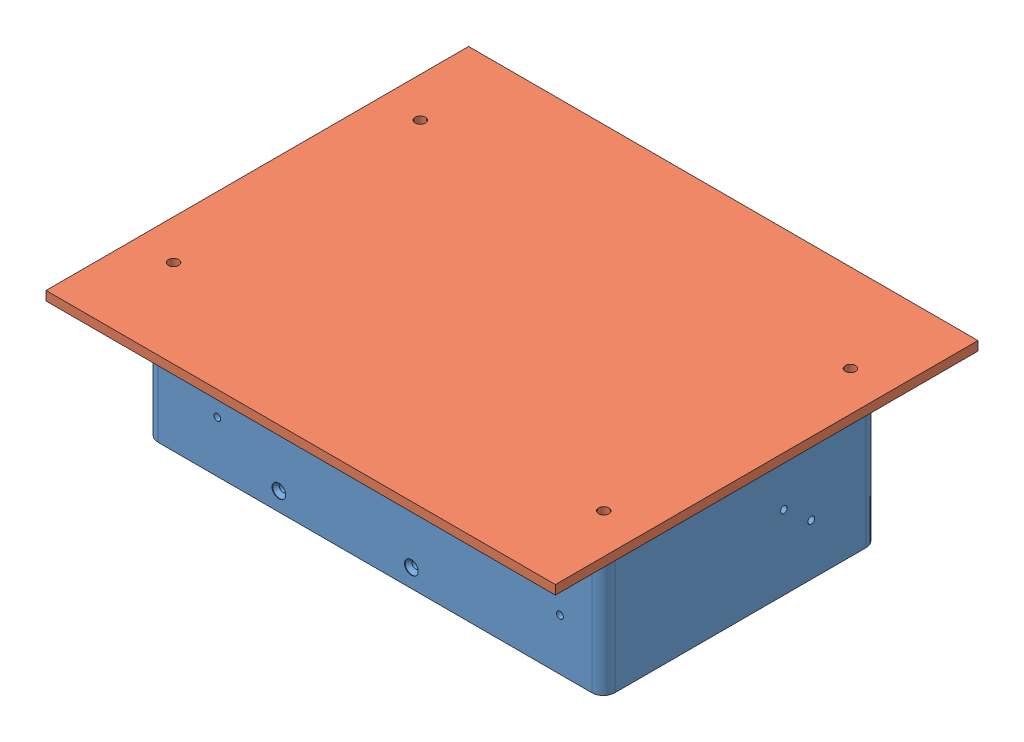
SolidWorks assembly multicomp-G373-milling, configuration Default. Lengths in mm.
Overall size (223 65.55 185).
2 component instances, 2 part files, 4 mates.
Components (placement in the parent):
- multicomp-G373-bottom-1: multicomp-G373-bottom [Modified for robot] at origin size (200 61.55 120)
- multicomp-G373-milling-mount-1: multicomp-G373-milling-mount [Default] at (0 61.55 0) x (1 0 0) z (0 1 0) size (223 185 4)
Mates (geometry in assembly coordinates):
- InPlace1: in place: plane of multicomp-G373-bottom-1 through (83.85 61.55 -52.7) normal (0 1 0); plane of multicomp-G373-milling-mount-1 through (0 61.55 0) normal (0 1 0); moOrthogonalPlaneRef_w of multicomp-G373-bottom-1 through (83.85 61.55 -52.7) normal (0 1 0); plane of multicomp-G373-milling-mount-1 through (0 61.55 0) normal (0 0 -1); plane of multicomp-G373-bottom-1 through (83.85 61.55 -52.7) normal (0 1 0); plane of multicomp-G373-milling-mount-1 through (0 61.55 0) normal (1 0 0); plane of multicomp-G373-bottom-1 through (83.85 61.55 -52.7) normal (0 1 0); unknown of multicomp-G373-milling-mount-1
- Coincident1: coincident aligned: plane of multicomp-G373-bottom-1; plane of multicomp-G373-milling-mount-1
- Coincident2: coincident aligned: moOrthogonalPlaneRef_w of multicomp-G373-bottom-1 through (0 61.55 0) normal (0 0 -1); plane of multicomp-G373-milling-mount-1 through (0 61.55 0) normal (0 0 -1)
- Coincident3: coincident anti-aligned: moOrthogonalPlaneRef_w of multicomp-G373-bottom-1 through (0 61.55 0) normal (-1 0 0); plane of multicomp-G373-milling-mount-1 through (0 61.55 0) normal (1 0 0)
